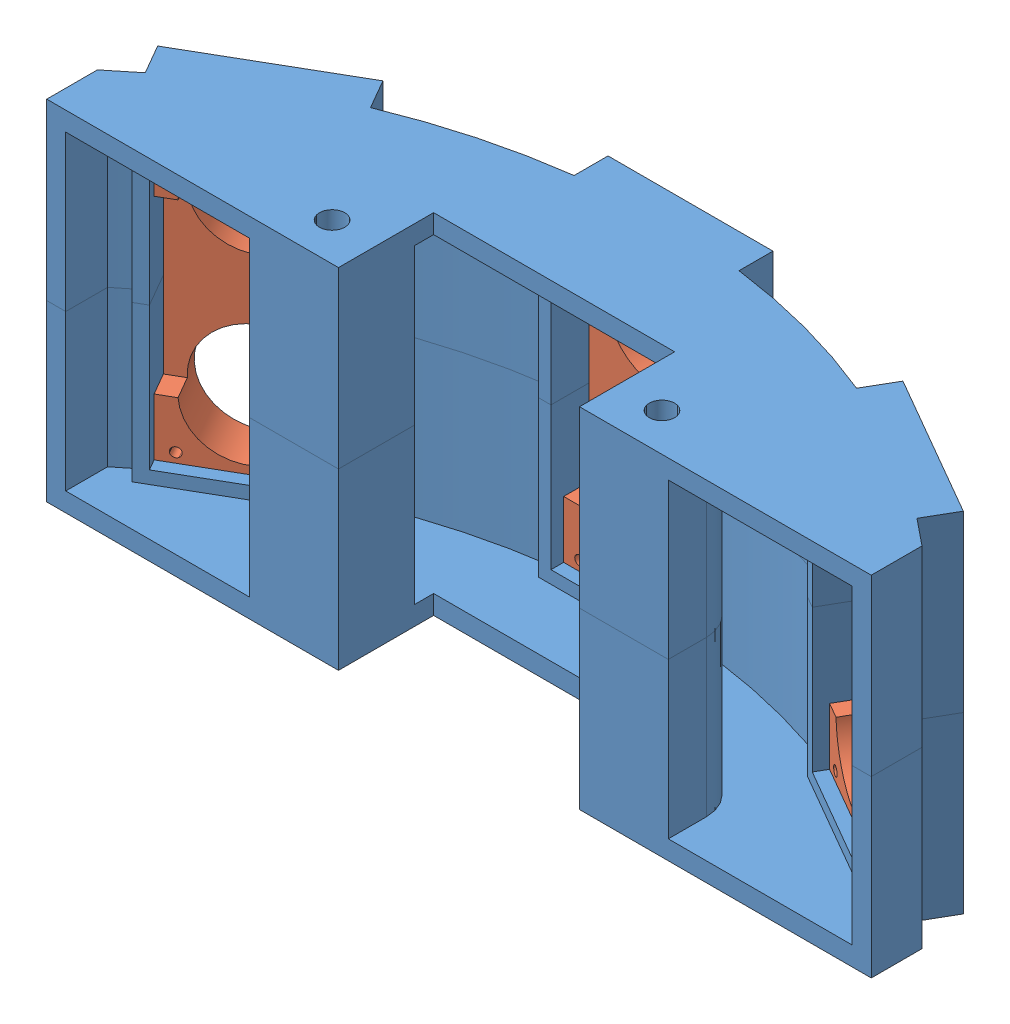
SolidWorks assembly 装配体2, configuration 默认. Lengths in mm.
Overall size (130 55 36.5).
5 component instances, 2 part files, 12 mates.
Components (placement in the parent):
- 车头前盖-1: 车头前盖 [默认] at (-3.1373 -12.0049 216.25) size (130 27.5 36.5)
- 车头前盖-2: 车头前盖 [默认] at (-3.1373 36.9951 216.25) x (-1 0 0) z (0 0 1) size (130 27.5 36.5)
- 超声波传感器安装板-1: 超声波传感器安装板 [默认] at (-3.1373 12.4951 113.75) x (1 0 0) z (0 -1 0) size (22 7 51)
- 超声波传感器安装板-2: 超声波传感器安装板 [默认] at (48.1127 12.4951 127.4824) x (0.866025 0 0.5) z (0 -1 0) size (22 7 51)
- 超声波传感器安装板-3: 超声波传感器安装板 [默认] at (-54.3873 12.4951 127.4824) x (0.866025 0 -0.5) z (0 -1 0) size (22 7 51)
Mates (geometry in assembly coordinates):
- 重合1: coincident: plane of 车头前盖-1 through (-3.1373 -13.0049 216.25) normal (0 1 0); plane of 超声波传感器安装板-1 through (7.8627 -13.0049 116.75) normal (0 -1 0)
- 重合2: coincident: plane of 车头前盖-1 through (-3.1373 -13.0049 113.75) normal (0 0 1); plane of 超声波传感器安装板-1 through (-3.1373 12.4951 113.75) normal (0 0 -1)
- 重合3: coincident anti-aligned: plane of 车头前盖-1 through (7.8627 12.4951 111.75) normal (-1 0 0); plane of 超声波传感器安装板-1 through (7.8627 37.9951 116.75) normal (1 0 0)
- 重合4: coincident: plane of 车头前盖-1 through (-3.1373 -13.0049 216.25) normal (0 1 0); plane of 超声波传感器安装板-3 through (-43.361 -13.0049 124.5805) normal (0 -1 0)
- 重合5: coincident: plane of 车头前盖-1 through (-45.861 12.4951 120.2503) normal (-0.866025 0 0.5); plane of 超声波传感器安装板-3 through (-43.361 37.9951 124.5805) normal (0.866025 0 -0.5)
- 重合6: coincident anti-aligned: plane of 车头前盖-1 through (-50.8873 -13.0049 133.5446) normal (-0.5 0 -0.866025); plane of 超声波传感器安装板-3 through (-50.8873 12.4951 133.5446) normal (0.5 0 0.866025)
- 重合7: coincident: plane of 车头前盖-1 through (-3.1373 -13.0049 216.25) normal (0 1 0); plane of 超声波传感器安装板-2 through (56.139 -13.0049 135.5805) normal (0 -1 0)
- 重合8: coincident: plane of 车头前盖-1 through (44.6127 -13.0049 133.5446) normal (0.5 0 -0.866025); plane of 超声波传感器安装板-2 through (44.6127 12.4951 133.5446) normal (-0.5 0 0.866025)
- 重合9: coincident anti-aligned: plane of 车头前盖-1 through (39.5865 12.4951 120.2503) normal (0.866025 0 0.5); plane of 超声波传感器安装板-2 through (37.0865 37.9951 124.5805) normal (-0.866025 0 -0.5)
- 重合10: coincident: plane of 车头前盖-1 through (-3.1373 -15.0049 148.25) normal (0 0 1); plane of 车头前盖-2 through (-3.1373 39.9951 148.25) normal (0 0 1)
- 重合11: coincident: plane of 车头前盖-1 through (61.8627 -15.0049 216.25) normal (1 0 0); plane of 车头前盖-2 through (61.8627 39.9951 216.25) normal (1 0 0)
- 重合12: coincident anti-aligned: plane of 车头前盖-1 through (-3.1373 12.4951 216.25) normal (0 1 0); plane of 车头前盖-2 through (-3.1373 12.4951 216.25) normal (0 -1 0)
